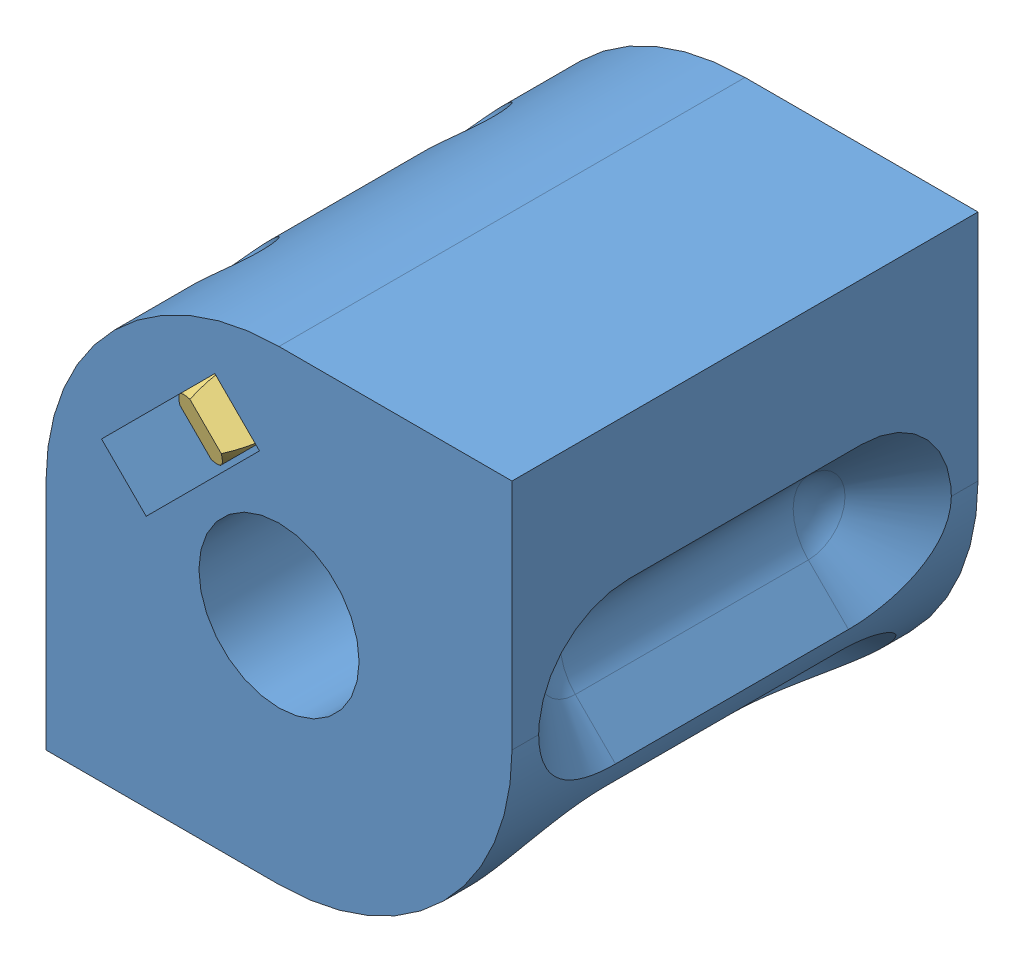
SolidWorks assembly Wing Fold Mechanism Rotary Detents, configuration Default. Lengths in mm.
Overall size (19.05 19.05 19.05).
5 component instances, 3 part files, 0 mates.
Components (placement in the parent):
- Wing Fold Mechanism Rotary Detents-1: Wing Fold Mechanism Rotary Detents [Default] at origin size (19.05 19.05 19.05)
- 92311A105-1: 92311A105 [Default] at (-4.0904 4.0904 33.3375) x (0.707107 0.707107 0) z (-0.707107 0.707107 0) size (2.91 2.9 4.84)
- 91841A005-1: 91841A005 [Default] at (-4.0972 4.0972 33.3375) x (0.707107 0.707107 0) z (0 0 1) size (6.35 2.56 7.33)
- 92311A105-2: 92311A105 [Default] at (-4.0904 4.0904 23.8125) x (0.707107 0.707107 0) z (-0.707107 0.707107 0) size (2.91 2.9 4.84)
- 91841A005-2: 91841A005 [Default] at (-4.0972 4.0972 23.8125) x (0.707107 0.707107 0) z (0 0 1) size (6.35 2.56 7.33)
